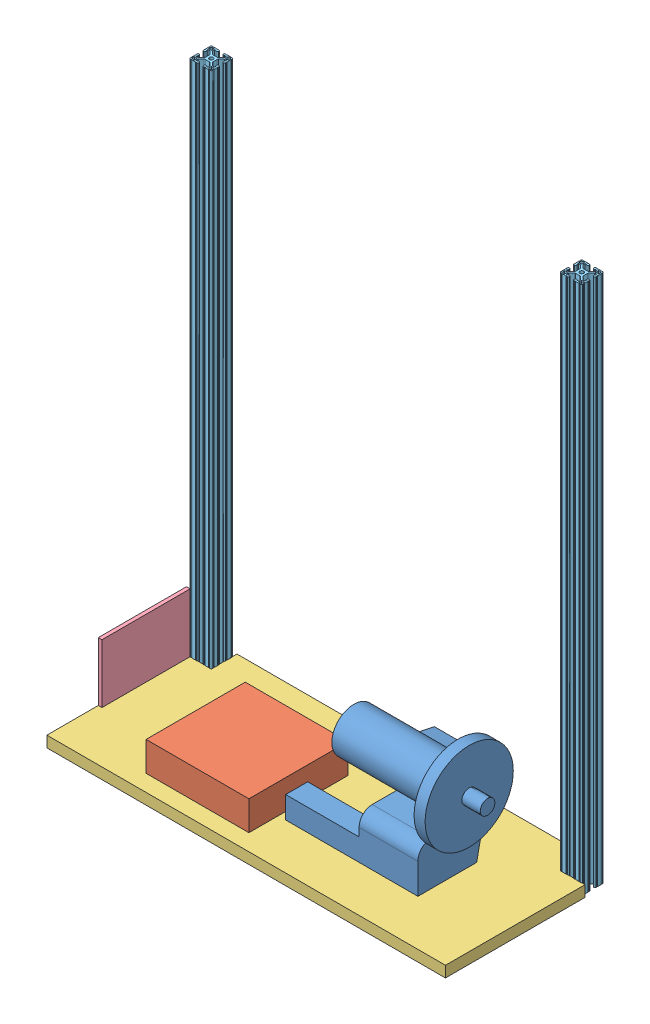
SolidWorks assembly Treadmill_Base_Assembly, configuration Default. Lengths in mm.
Overall size (688.98 914.4 285.75).
6 component instances, 5 part files, 5 mates.
Components (placement in the parent):
- MotorPart-1: MotorPart [Default] at (18.7698 115.7618 -249.1728) x (-1 0 0) z (0 0 -1) size (294.64 218.44 152.4)
- KBWT_Model-1: KBWT_Model [Default] at (-345.7202 26.8618 -229.7175) x (1 0 0) z (0 0 -1) size (177.8 53.34 171.45)
- TreadmillBase-1: TreadmillBase [Default] at (-577.4952 -42.9882 -115.4175) size (688.98 19.05 285.75)
- ButtonBaseModel-1: ButtonBaseModel [Default] at (-571.1452 26.8618 -280.5175) x (0 0 -1) z (-1 0 0) size (152.4 101.6 6.35)
- 47065T602_T-Slotted Framing-2: 47065T602_T-Slotted Framing [47065T602] at (87.1465 414.2118 -375.2467) x (1 0 0) z (0 -1 0) size (38.1 38.1 914.4)
- 47065T602_T-Slotted Framing-3: 47065T602_T-Slotted Framing [47065T602] at (-553.1619 414.2118 -375.2467) x (1 0 0) z (0 -1 0) size (38.1 38.1 914.4)
Mates (geometry in assembly coordinates):
- Coincident6: coincident: circle of MotorPart-1; circle of TreadmillBase-1
- Coincident8: coincident: point of TreadmillBase-1; point of ButtonBaseModel-1
- Coincident9: coincident: circle of KBWT_Model-1; circle of TreadmillBase-1
- Coincident11: coincident: point of assembly; point of assembly; point of TreadmillBase-1; moEndPointRef_w of 47065T602_T-Slotted Framing-2
- Coincident12: coincident: point of assembly; point of assembly; point of TreadmillBase-1; moEndPointRef_w of 47065T602_T-Slotted Framing-3
